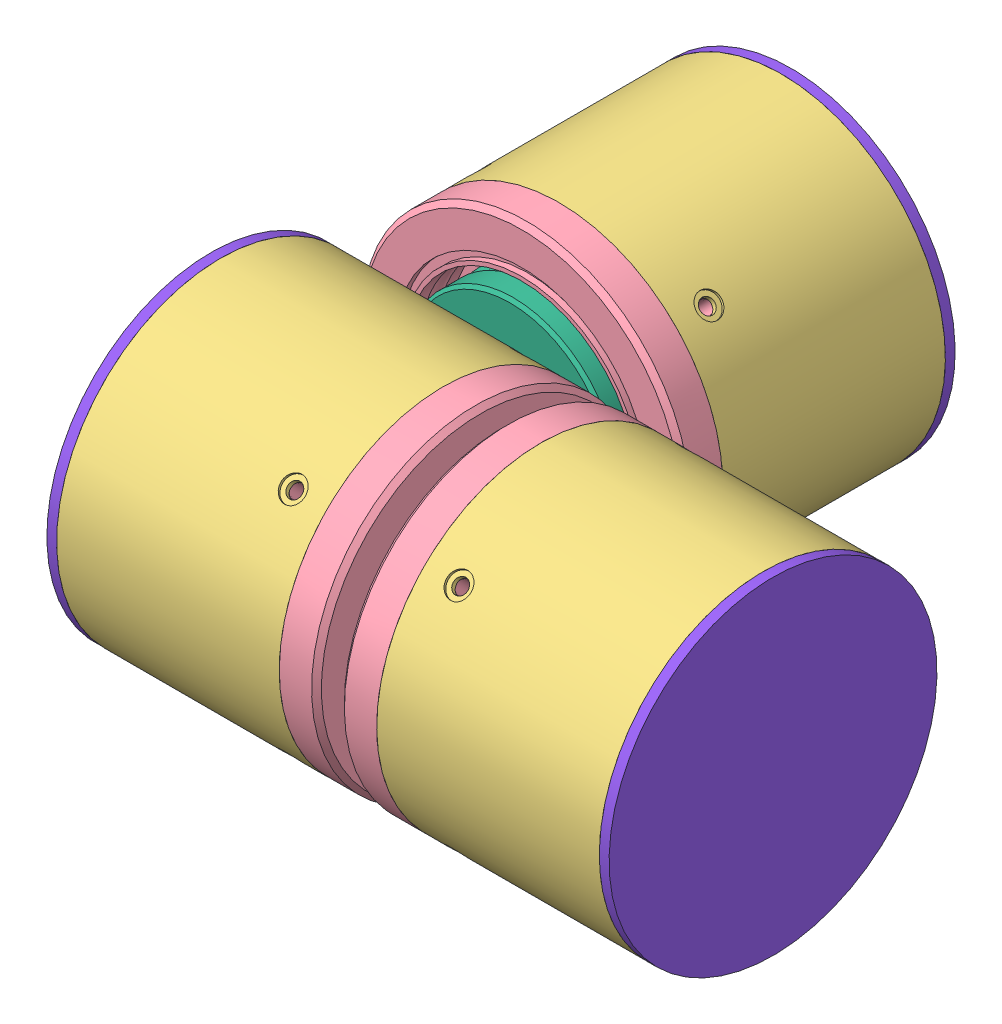
SolidWorks assembly robot_dog_one_leg, configuration 默认. Lengths in mm.
Overall size (134.03 96.37 137.76).
30 component instances, 8 part files, 2 mates.
Components (placement in the parent):
- bldc_reduction_driver-1: bldc_reduction_driver [Default] at (-40.4838 -36.7938 52.525) size (94.79 94.79 57.46)
  - bldc_base-1: bldc_base [默认] at (38.4559 43.1644 27.5347) size (63.02 63.02 5.5)
  - bldc_top-1: bldc_top [默认] at (38.4559 43.1644 34.0347) x (-0.070146 0.997537 0) z (0 0 1) size (63.02 63.02 17)
  - bldc_support-1: bldc_support [默认] at (38.4452 43.1532 25.5347) x (0.707605 0.706608 0) z (0 0 1) size (67.02 67.02 45.5)
  - bodyH40-1: bodyH40 [Default] at (38.4559 43.1644 59.8231) x (-0.706608 0.707605 0) z (0 0 -1) size (67.02 67.02 17.6)
  - Sun15H40-1: Sun15H40 [Default] at (38.4559 43.1644 53.0347) x (-0.997537 -0.070146 0) z (0 0 1) size (29.8 29.8 15.37)
  - Ring48H40-1: Ring48H40 [Default] at (38.4559 43.1644 67.0289) x (-0.966456 -0.256834 0) z (0 0 -1) size (42.67 42.67 10.37)
  - 3D_PCB4_2023-07-31.step-1: 3D_PCB4_2023-07-31.step [默认] at (17.4102 64.1183 15.8552) x (1 -0.000705 0) z (0 0 1) size (41.97 41.97 1.6)
    - COMPOUND.step-1: COMPOUND.step [默认] at origin size (41.97 41.97 1.6)
  - bldc_pcb_lid-1: bldc_pcb_lid [默认] at (38.4452 43.1532 13.5347) x (0.999669 -0.025711 0) z (-0.025711 -0.999669 0) size (67.02 2 67.02)
- bldc_reduction_driver-2: bldc_reduction_driver [Default] at (-43.8624 -38.3741 194.8628) x (0 0 -1) z (1 0 0) size (94.79 94.79 57.46)
  - bldc_base-1: bldc_base [默认] at (38.4559 43.1644 27.5347) size (63.02 63.02 5.5)
  - bldc_top-1: bldc_top [默认] at (38.4559 43.1644 34.0347) x (-0.070146 0.997537 0) z (0 0 1) size (63.02 63.02 17)
  - bldc_support-1: bldc_support [默认] at (38.4452 43.1532 25.5347) x (0.707605 0.706608 0) z (0 0 1) size (67.02 67.02 45.5)
  - bodyH40-1: bodyH40 [Default] at (38.4559 43.1644 59.8231) x (-0.706608 0.707605 0) z (0 0 -1) size (67.02 67.02 17.6)
  - Sun15H40-1: Sun15H40 [Default] at (38.4559 43.1644 53.0347) x (-0.997537 -0.070146 0) z (0 0 1) size (29.8 29.8 15.37)
  - Ring48H40-1: Ring48H40 [Default] at (38.4559 43.1644 67.0289) x (-0.966456 -0.256834 0) z (0 0 -1) size (42.67 42.67 10.37)
  - 3D_PCB4_2023-07-31.step-1: 3D_PCB4_2023-07-31.step [默认] at (17.4102 64.1183 15.8552) x (1 -0.000705 0) z (0 0 1) size (41.97 41.97 1.6)
    - COMPOUND.step-1: COMPOUND.step [默认] at origin size (41.97 41.97 1.6)
  - bldc_pcb_lid-1: bldc_pcb_lid [默认] at (38.4452 43.1532 13.5347) x (0.999669 -0.025711 0) z (-0.025711 -0.999669 0) size (67.02 2 67.02)
- bldc_reduction_driver-3: bldc_reduction_driver [Default] at (98.1353 -38.3741 117.9723) x (0 0 1) z (-1 0 0) size (94.79 94.79 57.46)
  - bldc_base-1: bldc_base [默认] at (38.4559 43.1644 27.5347) size (63.02 63.02 5.5)
  - bldc_top-1: bldc_top [默认] at (38.4559 43.1644 34.0347) x (-0.070146 0.997537 0) z (0 0 1) size (63.02 63.02 17)
  - bldc_support-1: bldc_support [默认] at (38.4452 43.1532 25.5347) x (0.707605 0.706608 0) z (0 0 1) size (67.02 67.02 45.5)
  - bodyH40-1: bodyH40 [Default] at (38.4559 43.1644 59.8231) x (-0.706608 0.707605 0) z (0 0 -1) size (67.02 67.02 17.6)
  - Sun15H40-1: Sun15H40 [Default] at (38.4559 43.1644 53.0347) x (-0.997537 -0.070146 0) z (0 0 1) size (29.8 29.8 15.37)
  - Ring48H40-1: Ring48H40 [Default] at (38.4559 43.1644 67.0289) x (-0.966456 -0.256834 0) z (0 0 -1) size (42.67 42.67 10.37)
  - 3D_PCB4_2023-07-31.step-1: 3D_PCB4_2023-07-31.step [默认] at (17.4102 64.1183 15.8552) x (1 -0.000705 0) z (0 0 1) size (41.97 41.97 1.6)
    - COMPOUND.step-1: COMPOUND.step [默认] at origin size (41.97 41.97 1.6)
  - bldc_pcb_lid-1: bldc_pcb_lid [默认] at (38.4452 43.1532 13.5347) x (0.999669 -0.025711 0) z (-0.025711 -0.999669 0) size (67.02 2 67.02)
Mates (geometry in assembly coordinates):
- Concentric1: concentric anti-aligned: cylinder of bldc_reduction_driver-2/bldc_support-1 through (-16.3277 4.7792 156.4175) axis (-1 0 0) radius 33.51; cylinder of bldc_reduction_driver-3/bldc_support-1 through (70.6006 4.7792 156.4175) axis (1 0 0) radius 33.51
- Coincident1: coincident anti-aligned: plane of bldc_reduction_driver-2/Ring48H40-1 through (27.1365 10.2701 135.7866) normal (1 0 0); plane of bldc_reduction_driver-3/Ring48H40-1 through (27.1365 10.2701 177.0484) normal (-1 0 0)
